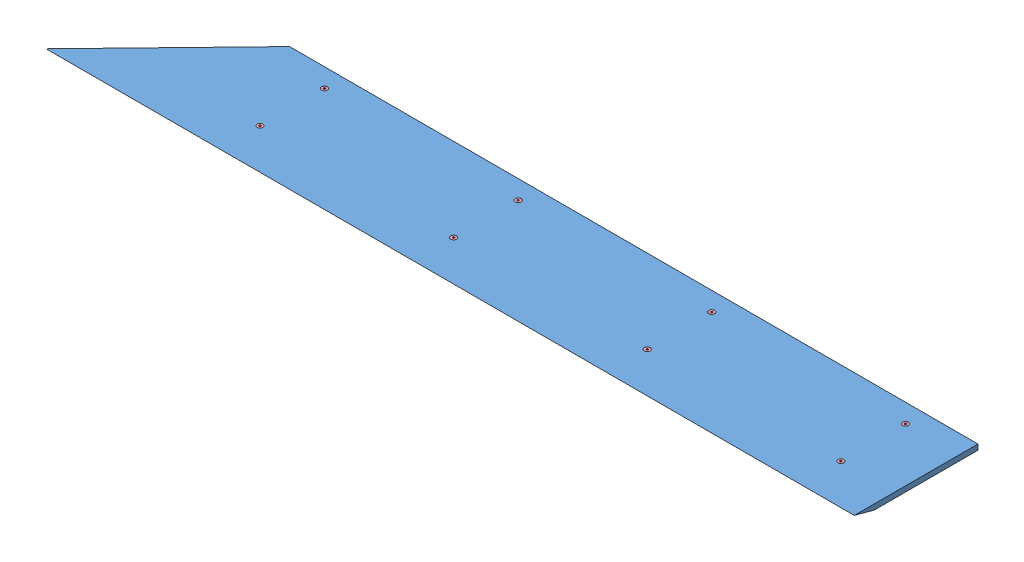
SolidWorks assembly GE-19060, configuration Default. Lengths in mm.
Overall size (1908.66 51.01 298.45).
21 component instances, 4 part files, 40 mates.
Components (placement in the parent):
- GE-19061-1: GE-19061 [Default] at (-11.9112 -4.3385 -141.1312) size (1908.66 12.7 292.1)
- GE-19055-1: GE-19055 [Default] at (-719.9362 -42.4385 -142.706) size (44.45 38.1 228.6)
- GE-19055-2: GE-19055 [Default] at (-262.7362 -42.4385 -142.706) size (44.45 38.1 228.6)
- GE-19055-3: GE-19055 [Default] at (194.4638 -42.4385 -142.706) size (44.45 38.1 228.6)
- GE-19055-4: GE-19055 [Default] at (651.6638 -42.4385 -142.706) size (44.45 38.1 228.6)
- nylock_.25_20-1: nylock_.25_20 [Default] at (673.8888 -9.1137 -96.6812) x (-0.837169 0 -0.546944) z (-0.546944 0 0.837169) size (11.11 7.94 12.83)
- nylock_.25_20-2: nylock_.25_20 [Default] at (673.8888 -9.1137 55.7188) x (-0.925243 0 -0.379375) z (-0.379375 0 0.925243) size (11.11 7.94 12.83)
- nylock_.25_20-3: nylock_.25_20 [Default] at (216.6888 -9.1137 55.7188) x (-0.985271 0 -0.170998) z (-0.170998 0 0.985271) size (11.11 7.94 12.83)
- nylock_.25_20-4: nylock_.25_20 [Default] at (216.6888 -9.1137 -96.6812) x (-0.997902 0 0.064746) z (0.064746 0 0.997902) size (11.11 7.94 12.83)
- nylock_.25_20-5: nylock_.25_20 [Default] at (-240.5112 -9.1137 -96.6812) x (-0.953572 0 0.301166) z (0.301166 0 0.953572) size (11.11 7.94 12.83)
- nylock_.25_20-6: nylock_.25_20 [Default] at (-240.5112 -9.1137 55.7188) x (-0.86157 0 0.507639) z (0.507639 0 0.86157) size (11.11 7.94 12.83)
- nylock_.25_20-7: nylock_.25_20 [Default] at (-697.7112 -9.1137 55.7188) x (-0.748019 0 0.663677) z (0.663677 0 0.748019) size (11.11 7.94 12.83)
- nylock_.25_20-8: nylock_.25_20 [Default] at (-697.7112 -9.1137 -96.6812) x (-0.643589 0 0.765371) z (0.765371 0 0.643589) size (11.11 7.94 12.83)
- flat_hex_.25_20_1-1: flat_hex_.25_20_1 [91253A542] at (673.8888 8.3615 -96.6812) x (1 0 0) z (0 1 0) size (13.49 13.49 25.61)
- flat_hex_.25_20_1-2: flat_hex_.25_20_1 [91253A542] at (673.8888 8.3615 55.7188) x (0.982082 0 -0.188455) z (0 1 0) size (13.49 13.49 25.61)
- flat_hex_.25_20_1-3: flat_hex_.25_20_1 [91253A542] at (216.6888 8.3615 55.7188) x (0.918365 0 -0.395734) z (0 1 0) size (13.49 13.49 25.61)
- flat_hex_.25_20_1-4: flat_hex_.25_20_1 [91253A542] at (216.6888 8.3615 -96.6812) x (0.8 0 -0.6) z (0 1 0) size (13.49 13.49 25.61)
- flat_hex_.25_20_1-5: flat_hex_.25_20_1 [91253A542] at (-240.5112 8.3615 -96.6812) x (0.63358 0 -0.773678) z (0 1 0) size (13.49 13.49 25.61)
- flat_hex_.25_20_1-6: flat_hex_.25_20_1 [91253A542] at (-240.5112 8.3615 55.7188) x (0.443629 0 -0.896211) z (0 1 0) size (13.49 13.49 25.61)
- flat_hex_.25_20_1-7: flat_hex_.25_20_1 [91253A542] at (-697.7112 8.3615 55.7188) x (0.263225 0 -0.964735) z (0 1 0) size (13.49 13.49 25.61)
- flat_hex_.25_20_1-8: flat_hex_.25_20_1 [91253A542] at (-697.7112 8.3615 -96.6812) x (0.120178 0 -0.992752) z (0 1 0) size (13.49 13.49 25.61)
Mates (geometry in assembly coordinates):
- Coincident1: coincident: plane of GE-19061-1 through (-11.9112 -4.3385 -141.1312) normal (0 -1 0); plane of GE-19055-1 through (-675.4862 -4.3385 81.1188) normal (0 1 0)
- Concentric1: concentric: cylinder of GE-19061-1 through (-697.7112 8.3615 -96.6812) axis (0 1 0) radius 3.5712; cylinder of GE-19055-1 through (-697.7112 -42.4385 -96.6812) axis (0 1 0) radius 3.3655
- Coincident2: coincident: plane of GE-19061-1 through (-11.9112 -4.3385 -141.1312) normal (0 -1 0); plane of GE-19055-2 through (-218.2862 -4.3385 81.1188) normal (0 1 0)
- Concentric2: concentric: cylinder of GE-19061-1 through (-240.5112 8.3615 -96.6812) axis (0 1 0) radius 3.5712; cylinder of GE-19055-2 through (-240.5112 -42.4385 -96.6812) axis (0 1 0) radius 3.3655
- Coincident3: coincident: plane of GE-19061-1 through (-11.9112 -4.3385 -141.1312) normal (0 -1 0); plane of GE-19055-3 through (238.9138 -4.3385 81.1188) normal (0 1 0)
- Concentric3: concentric: cylinder of GE-19061-1 through (216.6888 8.3615 -96.6812) axis (0 1 0) radius 3.5712; cylinder of GE-19055-3 through (216.6888 -42.4385 -96.6812) axis (0 1 0) radius 3.3655
- Coincident4: coincident: plane of GE-19061-1 through (-11.9112 -4.3385 -141.1312) normal (0 -1 0); plane of GE-19055-4 through (696.1138 -4.3385 81.1188) normal (0 1 0)
- Concentric4: concentric: cylinder of GE-19061-1 through (673.8888 8.3615 -96.6812) axis (0 1 0) radius 3.5712; cylinder of GE-19055-4 through (673.8888 -42.4385 -96.6812) axis (0 1 0) radius 3.3655
- Concentric5: concentric: cylinder of assembly; cylinder of assembly; cylinder of GE-19055-4 through (673.8888 -42.4385 -96.6812) axis (0 1 0) radius 3.3655; cylinder of nylock_.25_20-1 through (673.8888 -9.1137 -96.6812) axis (0 -1 0) radius 3.175
- Coincident5: coincident: plane of assembly; plane of assembly; plane of GE-19055-4 through (696.1138 -9.1137 -142.706) normal (0 -1 0); plane of nylock_.25_20-1 through (673.8888 -9.1137 -96.6812) normal (0 1 0)
- Coincident6: coincident: plane of assembly; plane of assembly; plane of GE-19055-4 through (696.1138 -9.1137 -142.706) normal (0 -1 0); plane of nylock_.25_20-2 through (673.8888 -9.1137 55.7188) normal (0 1 0)
- Concentric6: concentric: cylinder of assembly; cylinder of assembly; cylinder of GE-19055-4 through (673.8888 -42.4385 55.7188) axis (0 1 0) radius 3.3655; cylinder of nylock_.25_20-2 through (673.8888 -9.1137 55.7188) axis (0 -1 0) radius 3.175
- Coincident7: coincident: plane of assembly; plane of assembly; plane of GE-19055-4 through (696.1138 -9.1137 -142.706) normal (0 -1 0); plane of nylock_.25_20-3 through (216.6888 -9.1137 55.7188) normal (0 1 0)
- Concentric7: concentric: cylinder of assembly; cylinder of assembly; cylinder of GE-19055-3 through (216.6888 -42.4385 55.7188) axis (0 1 0) radius 3.3655; cylinder of nylock_.25_20-3 through (216.6888 -9.1137 55.7188) axis (0 -1 0) radius 3.175
- Coincident8: coincident: plane of assembly; plane of assembly; plane of GE-19055-4 through (696.1138 -9.1137 -142.706) normal (0 -1 0); plane of nylock_.25_20-4 through (216.6888 -9.1137 -96.6812) normal (0 1 0)
- Concentric8: concentric: cylinder of assembly; cylinder of assembly; cylinder of GE-19055-3 through (216.6888 -42.4385 -96.6812) axis (0 1 0) radius 3.3655; cylinder of nylock_.25_20-4 through (216.6888 -9.1137 -96.6812) axis (0 -1 0) radius 3.175
- Coincident9: coincident: plane of assembly; plane of assembly; plane of GE-19055-4 through (696.1138 -9.1137 -142.706) normal (0 -1 0); plane of nylock_.25_20-5 through (-240.5112 -9.1137 -96.6812) normal (0 1 0)
- Concentric9: concentric: cylinder of assembly; cylinder of assembly; cylinder of GE-19055-2 through (-240.5112 -42.4385 -96.6812) axis (0 1 0) radius 3.3655; cylinder of nylock_.25_20-5 through (-240.5112 -9.1137 -96.6812) axis (0 -1 0) radius 3.175
- Coincident10: coincident: plane of assembly; plane of assembly; plane of GE-19055-4 through (696.1138 -9.1137 -142.706) normal (0 -1 0); plane of nylock_.25_20-6 through (-240.5112 -9.1137 55.7188) normal (0 1 0)
- Concentric10: concentric: cylinder of assembly; cylinder of assembly; cylinder of GE-19055-2 through (-240.5112 -42.4385 55.7188) axis (0 1 0) radius 3.3655; cylinder of nylock_.25_20-6 through (-240.5112 -9.1137 55.7188) axis (0 -1 0) radius 3.175
- Coincident11: coincident: plane of assembly; plane of assembly; plane of GE-19055-4 through (696.1138 -9.1137 -142.706) normal (0 -1 0); plane of nylock_.25_20-7 through (-697.7112 -9.1137 55.7188) normal (0 1 0)
- Concentric11: concentric: cylinder of assembly; cylinder of assembly; cylinder of GE-19055-1 through (-697.7112 -42.4385 55.7188) axis (0 1 0) radius 3.3655; cylinder of nylock_.25_20-7 through (-697.7112 -9.1137 55.7188) axis (0 -1 0) radius 3.175
- Coincident12: coincident: plane of assembly; plane of assembly; plane of GE-19055-4 through (696.1138 -9.1137 -142.706) normal (0 -1 0); plane of nylock_.25_20-8 through (-697.7112 -9.1137 -96.6812) normal (0 1 0)
- Concentric12: concentric: cylinder of assembly; cylinder of assembly; cylinder of GE-19055-1 through (-697.7112 -42.4385 -96.6812) axis (0 1 0) radius 3.3655; cylinder of nylock_.25_20-8 through (-697.7112 -9.1137 -96.6812) axis (0 -1 0) radius 3.175
- Concentric13: concentric: cylinder of GE-19061-1 through (673.8888 8.3615 -96.6812) axis (0 1 0) radius 3.5712; cylinder of flat_hex_.25_20_1-1 through (673.8888 -17.0385 -96.6812) axis (0 -1 0) radius 3.175
- Coincident14: coincident: plane of GE-19061-1 through (-11.9112 8.3615 -141.1312) normal (0 1 0); plane of flat_hex_.25_20_1-1 through (673.8888 8.3615 -93.5062) normal (0 1 0)
- Coincident15: coincident: plane of GE-19061-1 through (-11.9112 8.3615 -141.1312) normal (0 1 0); plane of flat_hex_.25_20_1-2 through (674.4871 8.3615 58.8369) normal (0 1 0)
- Concentric14: concentric: cylinder of GE-19061-1 through (673.8888 8.3615 55.7188) axis (0 1 0) radius 3.5712; cylinder of flat_hex_.25_20_1-2 through (673.8888 -17.0385 55.7188) axis (0 -1 0) radius 3.175
- Coincident16: coincident: plane of GE-19061-1 through (-11.9112 8.3615 -141.1312) normal (0 1 0); plane of flat_hex_.25_20_1-3 through (217.9452 8.3615 58.6346) normal (0 1 0)
- Concentric15: concentric: cylinder of GE-19061-1 through (216.6888 8.3615 55.7188) axis (0 1 0) radius 3.5712; cylinder of flat_hex_.25_20_1-3 through (216.6888 -17.0385 55.7188) axis (0 -1 0) radius 3.175
- Coincident17: coincident: plane of GE-19061-1 through (-11.9112 8.3615 -141.1312) normal (0 1 0); plane of flat_hex_.25_20_1-4 through (218.5938 8.3615 -94.1412) normal (0 1 0)
- Concentric16: concentric: cylinder of GE-19061-1 through (216.6888 8.3615 -96.6812) axis (0 1 0) radius 3.5712; cylinder of flat_hex_.25_20_1-4 through (216.6888 -17.0385 -96.6812) axis (0 -1 0) radius 3.175
- Coincident18: coincident: plane of GE-19061-1 through (-11.9112 8.3615 -141.1312) normal (0 1 0); plane of flat_hex_.25_20_1-5 through (-238.0548 8.3615 -94.6696) normal (0 1 0)
- Concentric17: concentric: cylinder of GE-19061-1 through (-240.5112 8.3615 -96.6812) axis (0 1 0) radius 3.5712; cylinder of flat_hex_.25_20_1-5 through (-240.5112 -17.0385 -96.6812) axis (0 -1 0) radius 3.175
- Coincident19: coincident: plane of GE-19061-1 through (-11.9112 8.3615 -141.1312) normal (0 1 0); plane of flat_hex_.25_20_1-6 through (-237.6658 8.3615 57.1273) normal (0 1 0)
- Concentric18: concentric: cylinder of GE-19061-1 through (-240.5112 8.3615 55.7188) axis (0 1 0) radius 3.5712; cylinder of flat_hex_.25_20_1-6 through (-240.5112 -17.0385 55.7188) axis (0 -1 0) radius 3.175
- Coincident20: coincident: plane of GE-19061-1 through (-11.9112 8.3615 -141.1312) normal (0 1 0); plane of flat_hex_.25_20_1-7 through (-694.6482 8.3615 56.5545) normal (0 1 0)
- Concentric19: concentric: cylinder of GE-19061-1 through (-697.7112 8.3615 55.7188) axis (0 1 0) radius 3.5712; cylinder of flat_hex_.25_20_1-7 through (-697.7112 -17.0385 55.7188) axis (0 -1 0) radius 3.175
- Coincident21: coincident: plane of GE-19061-1 through (-11.9112 8.3615 -141.1312) normal (0 1 0); plane of flat_hex_.25_20_1-8 through (-694.5592 8.3615 -96.2997) normal (0 1 0)
- Concentric20: concentric: cylinder of GE-19061-1 through (-697.7112 8.3615 -96.6812) axis (0 1 0) radius 3.5712; cylinder of flat_hex_.25_20_1-8 through (-697.7112 -17.0385 -96.6812) axis (0 -1 0) radius 3.175
